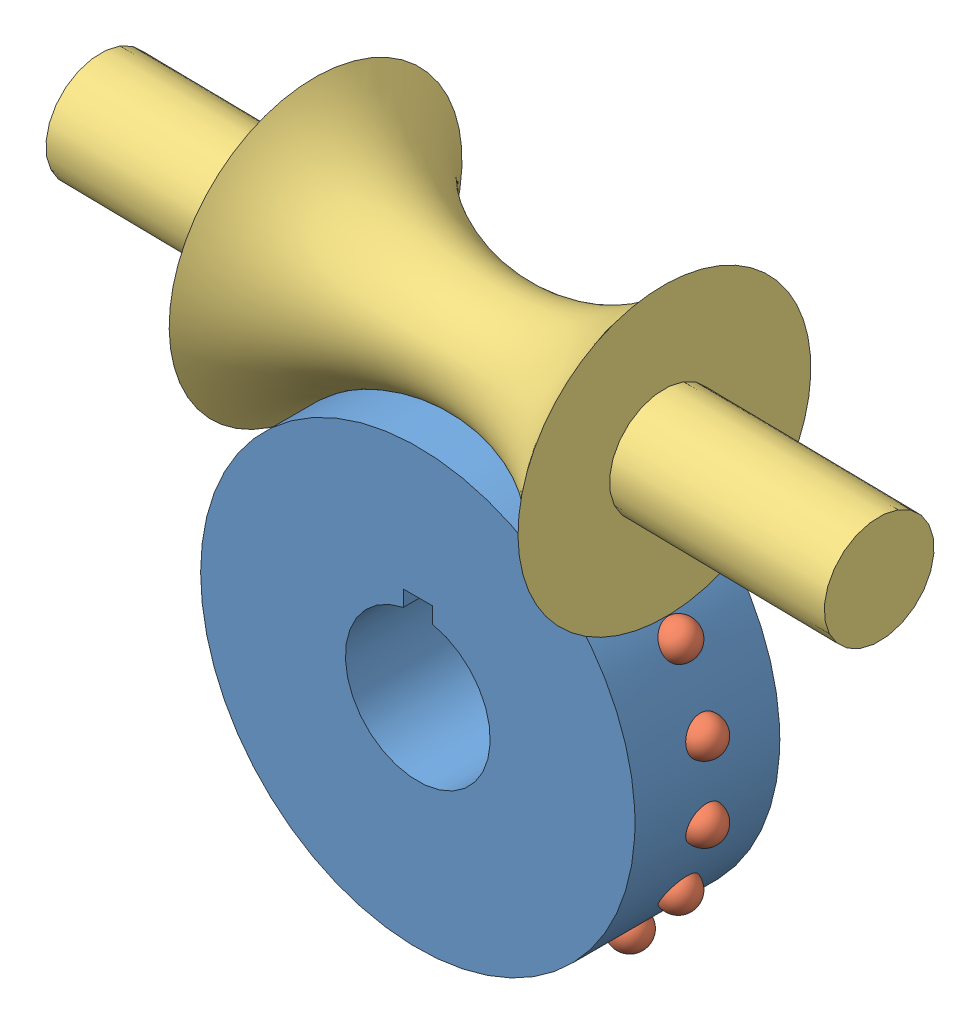
SolidWorks assembly Assemblage1, configuration Défaut. Lengths in mm.
Overall size (110.02 118.4 97.42).
20 component instances, 3 part files, 18 mates.
Components (placement in the parent):
- Roue-1: Roue [Défaut] at (-1.9371 -2.1187 0) size (60 60 20)
- bille-1: bille [Défaut] at (8.3235 26.0721 10) size (5 5 5)
- bille-2: bille [Défaut] at (24.0436 12.8813 10) size (5 5 5)
- bille-3: bille [Défaut] at (27.6071 3.0907 10) size (5 5 5)
- bille-4: bille [Défaut] at (17.3465 20.8626 10) size (5 5 5)
- bille-5: bille [Défaut] at (27.6071 -7.3282 10) size (5 5 5)
- bille-6: bille [Défaut] at (24.0436 -17.1187 10) size (5 5 5)
- bille-7: bille [Défaut] at (17.3465 -25.1001 10) size (5 5 5)
- bille-8: bille [Défaut] at (-1.9371 27.8813 10) size (5 5 5)
- bille-9: bille [Défaut] at (-12.1977 26.0721 10) size (5 5 5)
- bille-10: bille [Défaut] at (-21.2207 20.8626 10) x (0.964652 0.250588 0.081558) z (-0.082521 -0.006682 0.996567) size (5 5 5)
- bille-11: bille [Défaut] at (-27.9179 12.8813 10) size (5 5 5)
- bille-12: bille [Défaut] at (-31.4814 3.0907 10) size (5 5 5)
- bille-13: bille [Défaut] at (-31.4814 -7.3282 10) size (5 5 5)
- bille-14: bille [Défaut] at (-27.9179 -17.1187 10) size (5 5 5)
- bille-15: bille [Défaut] at (-21.2207 -25.1001 10) size (5 5 5)
- bille-16: bille [Défaut] at (-12.1977 -30.3095 10) size (5 5 5)
- bille-17: bille [Défaut] at (-1.9371 -32.1187 10) size (5 5 5)
- bille-18: bille [Défaut] at (8.3235 -30.3095 10) size (5 5 5)
- Vis-1: Vis [Défaut] at (-1.311 35.4325 10.6544) x (0.999926 -0.004574 0.01129) z (-0.009031 0.34357 0.939084) size (108.73 75 75)
Mates (geometry in assembly coordinates):
- Coaxiale1: concentric: sphere of Roue-1; sphere of bille-1
- Coaxiale2: concentric: sphere of Roue-1; sphere of bille-4
- Coaxiale3: concentric: sphere of Roue-1; sphere of bille-2
- Coaxiale4: concentric: sphere of Roue-1; sphere of bille-3
- Coaxiale5: concentric: sphere of Roue-1; sphere of bille-5
- Coaxiale6: concentric: sphere of Roue-1; sphere of bille-6
- Coaxiale7: concentric: sphere of Roue-1; sphere of bille-7
- Coaxiale8: concentric: sphere of Roue-1; sphere of bille-8
- Coaxiale9: concentric: sphere of Roue-1; sphere of bille-9
- Coaxiale10: concentric: sphere of Roue-1; sphere of bille-10
- Coaxiale11: concentric: sphere of Roue-1; sphere of bille-11
- Coaxiale12: concentric: sphere of Roue-1; sphere of bille-12
- Coaxiale13: concentric: sphere of Roue-1; sphere of bille-13
- Coaxiale14: concentric: sphere of Roue-1; sphere of bille-14
- Coaxiale15: concentric: sphere of Roue-1; sphere of bille-15
- Coaxiale16: concentric: sphere of Roue-1; sphere of bille-16
- Coaxiale17: concentric: sphere of Roue-1; sphere of bille-17
- Coaxiale18: concentric: sphere of Roue-1; sphere of bille-18
